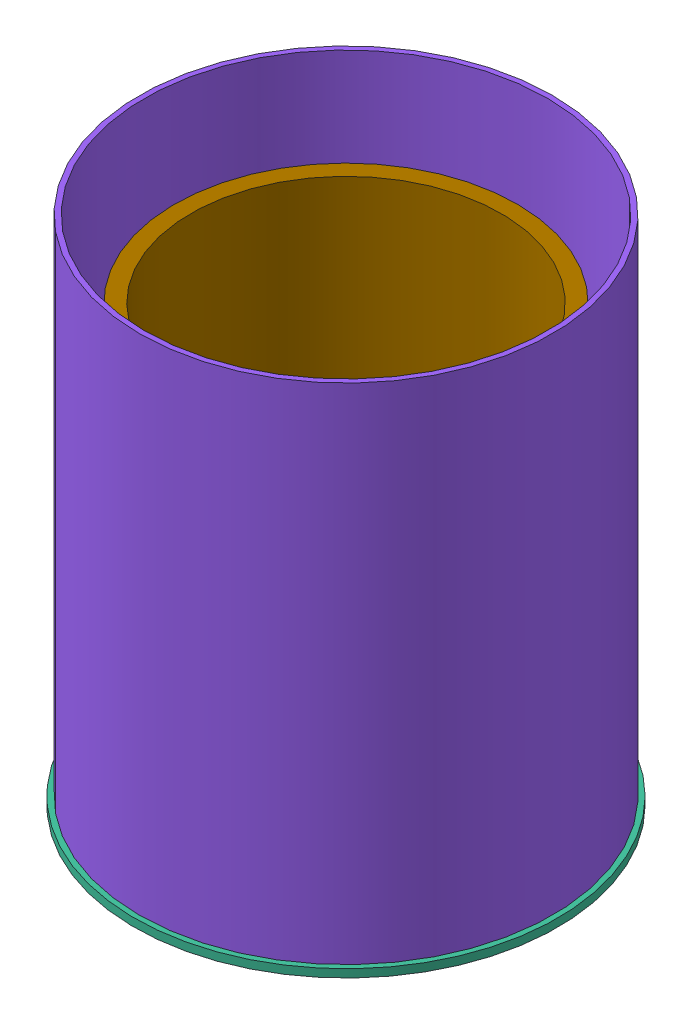
SolidWorks assembly Dispensador, configuration Valor predeterminado. Lengths in mm.
Overall size (296.98 254 296.98).
16 component instances, 9 part files, 37 mates.
Components (placement in the parent):
- Ring-1: Ring [Valor predeterminado] at origin size (200 4 200)
- Sun-1: Sun [Valor predeterminado] x (-0.139266 0 0.990255) z (-0.990255 0 -0.139266) size (51.55 4 51.02)
- planet-1: planet [Valor predeterminado] at (-44 0 0) x (0.841431 0 0.540365) z (-0.540365 0 0.841431) size (51.76 4 51.23)
- planet-2: planet [Valor predeterminado] at (44 0 0) size (51.76 4 51.23)
- planet-3: planet [Valor predeterminado] at (0 0 -44) x (0.959574 0 -0.281457) z (0.281457 0 0.959574) size (51.76 4 51.23)
- planet-4: planet [Valor predeterminado] at (0 0 44) x (0.961456 0 0.274958) z (-0.274958 0 0.961456) size (51.76 4 51.23)
- Rolamento1-1: Rolamento1 [Valor predeterminado] at (-44 0 0) x (0.679589 0 0.733593) z (-0.733593 0 0.679589) size (22 7 22)
- Rolamento1-2: Rolamento1 [Valor predeterminado] at (0 0 -44) size (22 7 22)
- Rolamento1-3: Rolamento1 [Valor predeterminado] at (44 0 0) size (22 7 22)
- Rolamento1-4: Rolamento1 [Valor predeterminado] at (0 0 44) size (22 7 22)
- base_mecanismo-1: base_mecanismo [Valor predeterminado] at (0 4 0) size (200 4 200)
- Base-1: Base [Valor predeterminado] at (0 -4 0) x (0.707107 0 0.707107) z (-0.707107 0 0.707107) size (210 4 210)
- Piso-1: Piso [Valor predeterminado] at (0 7 0) size (168 4 168)
- Parede Lateral-1: Parede Lateral [Valor predeterminado] at origin size (205 250 205)
- base_mecanismo-2: base_mecanismo [Valor predeterminado] at (0 8 0) size (200 4 200)
- circulo interno-1: circulo interno [Valor predeterminado] at (0 12 0) size (168.26 200 170)
Mates (geometry in assembly coordinates):
- Concêntrico6: concentric: circle of ?
- Coincidente5: coincident: plane of Ring-1 through (0 0 0) normal (0 -1 0); plane of assembly through (0 0 0) normal (0 1 0)
- Concêntrico7: concentric: cylinder of Sun-1 through (0 4 0) axis (0 -1 0) radius 4; circle of assembly
- Coincidente6: coincident: point of planet-1; circle of assembly
- Coincidente7: coincident: plane of planet-1 through (-51.9256 0 17.0786) normal (0 -1 0); plane of assembly through (0 0 0) normal (0 1 0)
- Coincidente8: coincident: plane of Sun-1 through (15.7952 0 -10.192) normal (0 -1 0); plane of assembly through (0 0 0) normal (0 1 0)
- Coincidente11: coincident: point of planet-1; line of assembly
- Coincidente12: coincident: plane of planet-2 through (46.5598 0 18.6532) normal (0 -1 0); plane of assembly through (0 0 0) normal (0 1 0)
- Coincidente13: coincident: point of planet-2; line of assembly
- Coincidente14: coincident: point of planet-2; circle of assembly
- Coincidente15: coincident: plane of planet-3 through (7.7064 0 -26.8213) normal (0 -1 0); plane of assembly through (0 0 0) normal (0 1 0)
- Coincidente16: coincident: point of planet-3; circle of assembly
- Coincidente17: coincident: point of planet-3; line of assembly
- Coincidente18: coincident: plane of planet-4 through (-2.6677 0 62.6381) normal (0 -1 0); plane of assembly through (0 0 0) normal (0 1 0)
- Coincidente19: coincident: point of planet-4; line of assembly
- Coincidente20: coincident: point of planet-4; circle of assembly
- Coincidente21: coincident: plane of planet-1 through (-44 0 0) normal (0 1 0); plane of Rolamento1-1 through (-44 0 0) normal (0 -1 0)
- Concêntrico9: concentric: cylinder of planet-1 through (-44 4 0) axis (0 -1 0) radius 11; cylinder of Rolamento1-1 through (-44 7 0) axis (0 -1 0) radius 11
- Coincidente22: coincident: plane of Rolamento1-2 through (0 0 -44) normal (0 -1 0); plane of assembly through (0 0 0) normal (0 1 0)
- Concêntrico10: concentric: cylinder of planet-3 through (0 4 -44) axis (0 -1 0) radius 11; cylinder of Rolamento1-2 through (0 7 -44) axis (0 -1 0) radius 11
- Coincidente23: coincident: plane of Rolamento1-3 through (44 0 0) normal (0 -1 0); plane of assembly through (0 0 0) normal (0 1 0)
- Concêntrico11: concentric: cylinder of planet-2 through (44 4 0) axis (0 -1 0) radius 11; cylinder of Rolamento1-3 through (44 7 0) axis (0 -1 0) radius 11
- Coincidente24: coincident: plane of Rolamento1-4 through (0 0 44) normal (0 -1 0); plane of assembly through (0 0 0) normal (0 1 0)
- Concêntrico12: concentric: cylinder of planet-4 through (0 4 44) axis (0 -1 0) radius 11; cylinder of Rolamento1-4 through (0 7 44) axis (0 -1 0) radius 11
- Coincidente25: coincident: plane of Ring-1 through (0 4 0) normal (0 1 0); plane of base_mecanismo-1 through (0 4 0) normal (0 -1 0)
- Concêntrico13: concentric: cylinder of Ring-1 through (0 4 0) axis (0 -1 0) radius 100; cylinder of base_mecanismo-1 through (0 8 0) axis (0 -1 0) radius 100
- Coincidente26: coincident: plane of Ring-1 through (0 0 0) normal (0 -1 0); plane of Base-1 through (0 0 0) normal (0 1 0)
- Concêntrico14: concentric: cylinder of Ring-1 through (0 4 0) axis (0 -1 0) radius 100; cylinder of Base-1 through (0 0 0) axis (0 -1 0) radius 105
- Coincidente27: coincident: plane of Rolamento1-2 through (0 7 -44) normal (0 1 0); plane of Piso-1 through (0 7 0) normal (0 -1 0)
- Concêntrico15: concentric: cylinder of base_mecanismo-1 through (0 8 0) axis (0 -1 0) radius 85; cylinder of Piso-1 through (0 11 0) axis (0 -1 0) radius 84
- Coincidente28: coincident: plane of Base-1 through (0 0 0) normal (0 1 0); plane of Parede Lateral-1 through (0 0 0) normal (0 -1 0)
- Concêntrico16: concentric: cylinder of Base-1 through (0 0 0) axis (0 -1 0) radius 105; cylinder of Parede Lateral-1 through (0 250 0) axis (0 -1 0) radius 102.5
- Coincidente29: coincident: plane of base_mecanismo-1 through (0 8 0) normal (0 1 0); plane of base_mecanismo-2 through (0 8 0) normal (0 -1 0)
- Concêntrico17: concentric: cylinder of base_mecanismo-1 through (0 8 0) axis (0 -1 0) radius 100; cylinder of base_mecanismo-2 through (0 12 0) axis (0 -1 0) radius 100
- Coincidente30: coincident: circle of Rolamento1-4; cylinder of Base-1 through (0 -10 44) axis (0 1 0) radius 4
- Coincidente31: coincident: plane of base_mecanismo-2 through (0 12 0) normal (0 1 0); plane of circulo interno-1 through (0 12 0) normal (0 -1 0)
- Concêntrico18: concentric: cylinder of Base-1 through (0 0 0) axis (0 -1 0) radius 105; cylinder of circulo interno-1 through (0 212 0) axis (0 -1 0) radius 85
